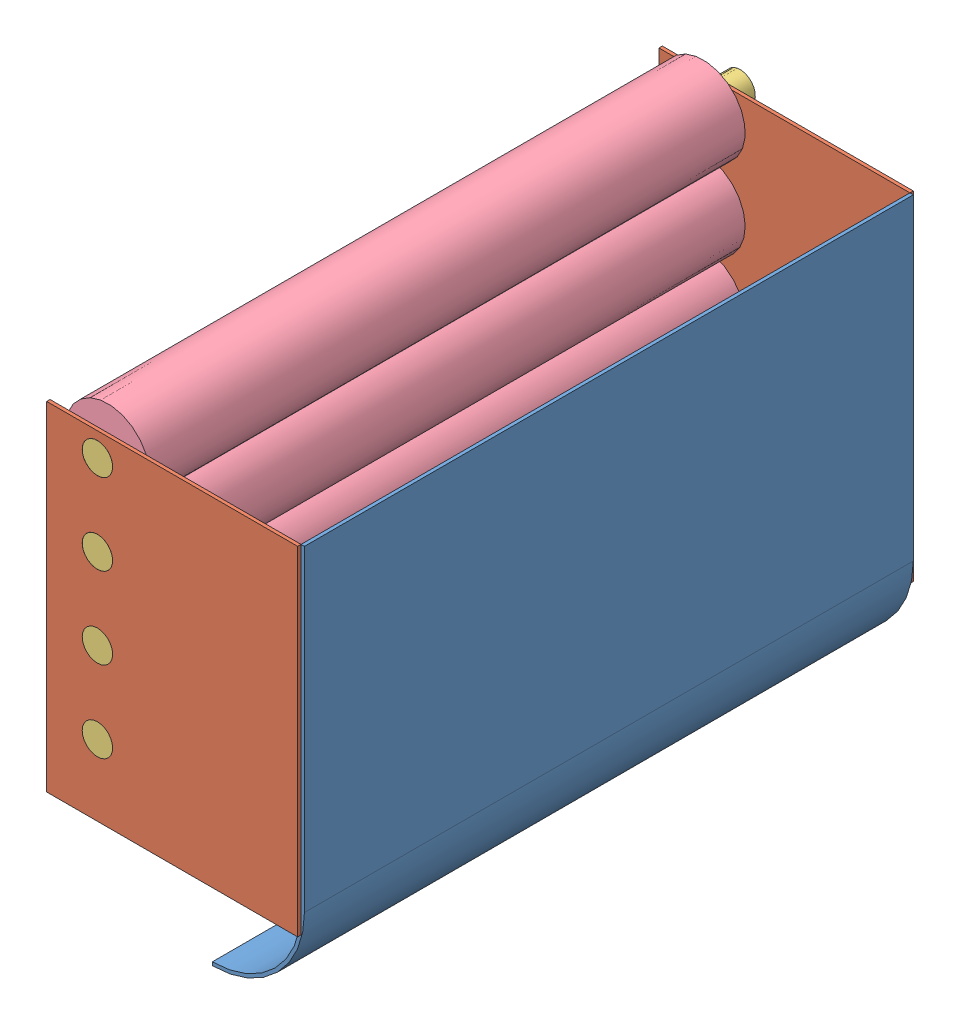
SolidWorks assembly bubbler, configuration Default. Lengths in mm.
Overall size (197.8 331.55 482.6).
11 component instances, 4 part files, 19 mates.
Components (placement in the parent):
- lift-1: lift [Default] at (342.8112 310.4383 211.2872) size (69.22 307.34 457.2)
- plate-1: plate [Default] at (344.2082 421.5633 208.7472) size (188.47 254 2.54)
- plate-2: plate [Default] at (344.2082 421.5633 668.4872) size (188.47 254 2.54)
- axel-1: axel [Default] at (259.1182 530.7833 188.4272) x (0.417742 -0.908566 0) z (0 0 1) size (22.86 22.86 482.6)
- roller-1: roller [Default] at (259.1182 530.7833 216.3672) x (-0.410534 0.911846 0) z (0 0 1) size (63.5 63.5 447.04)
- roller-2: roller [Default] at (259.1182 347.9033 216.3672) x (0.425663 0.904882 0) z (0 0 1) size (63.5 63.5 447.04)
- roller-3: roller [Default] at (259.1182 408.8633 216.3672) x (0.960453 -0.278441 0) z (0 0 1) size (63.5 63.5 447.04)
- roller-4: roller [Default] at (259.1182 469.8233 216.3672) x (0.696531 0.717526 0) z (0 0 1) size (63.5 63.5 447.04)
- axel-2: axel [Default] at (259.1182 408.8633 188.4272) size (22.86 22.86 482.6)
- axel-3: axel [Default] at (259.1182 469.8233 188.4272) x (-0.987013 0.160641 0) z (0 0 1) size (22.86 22.86 482.6)
- axel-4: axel [Default] at (259.1182 347.9033 188.4272) size (22.86 22.86 482.6)
Mates (geometry in assembly coordinates):
- Coincident4: coincident aligned: line of lift-1 through (409.4862 548.5633 668.4872) axis (1 0 0); line of plate-2 through (221.0182 548.5633 668.4872) axis (1 0 0)
- Coincident9: coincident aligned: plane of lift-1 through (409.4862 548.5633 668.4872) normal (0 1 0); plane of plate-2 through (221.0182 548.5633 671.0272) normal (0 1 0)
- Coincident10: coincident aligned: circle of plate-2; circle of axel-1
- Concentric1: concentric anti-aligned: cylinder of axel-1 through (259.1182 530.7833 671.0272) axis (0 0 -1) radius 11.43; cylinder of roller-1 through (259.1182 530.7833 216.3672) axis (0 0 1) radius 11.43
- Coincident12: coincident aligned: circle of plate-2; circle of axel-3
- Coincident14: coincident aligned: circle of plate-2; circle of axel-2
- Coincident16: coincident aligned: circle of plate-2; circle of axel-4
- Coincident17: coincident anti-aligned: circle of roller-4; cylinder of axel-3 through (259.1182 469.8233 671.0272) axis (0 0 -1) radius 11.43
- Concentric2: concentric anti-aligned: cylinder of roller-3 through (259.1182 408.8633 216.3672) axis (0 0 1) radius 11.43; cylinder of axel-2 through (259.1182 408.8633 671.0272) axis (0 0 -1) radius 11.43
- Coincident19: coincident anti-aligned: line of lift-1 through (409.4862 310.4383 668.4872) axis (0 1 0); line of plate-2 through (409.4862 548.5633 668.4872) axis (0 -1 0)
- Coincident20: coincident anti-aligned: line of lift-1 through (409.4862 310.4383 211.2872) axis (0 1 0); line of plate-1 through (409.4862 548.5633 211.2872) axis (0 -1 0)
- Concentric3: concentric anti-aligned: cylinder of roller-2 through (259.1182 347.9033 216.3672) axis (0 0 1) radius 11.43; cylinder of axel-4 through (259.1182 347.9033 671.0272) axis (0 0 -1) radius 11.43
- Parallel5: parallel aligned: plane of lift-1 through (342.8112 310.4383 211.2872) normal (0 0 -1); plane of plate-2 through (344.2082 421.5633 668.4872) normal (0 0 -1)
- Parallel6: parallel aligned: plane of plate-1 through (344.2082 421.5633 211.2872) normal (0 0 1); plane of plate-2 through (344.2082 421.5633 671.0272) normal (0 0 1)
- Coincident23: coincident aligned: plane of lift-1 through (409.4862 548.5633 668.4872) normal (0 1 0); plane of plate-1 through (221.0182 548.5633 211.2872) normal (0 1 0)
- Width1: width aligned: plane of roller-1 through (259.1182 530.7833 216.3672) normal (0 0 -1); plane of roller-1 through (259.1182 530.7833 663.4072) normal (0 0 1); plane of plate-2 through (344.2082 421.5633 668.4872) normal (0 0 -1); plane of plate-1 through (344.2082 421.5633 211.2872) normal (0 0 1)
- Width2: width aligned: plane of roller-4 through (259.1182 469.8233 663.4072) normal (0 0 1); plane of roller-4 through (259.1182 469.8233 216.3672) normal (0 0 -1); plane of plate-1 through (344.2082 421.5633 211.2872) normal (0 0 1); plane of plate-2 through (344.2082 421.5633 668.4872) normal (0 0 -1)
- Width3: width anti-aligned: plane of roller-3 through (259.1182 408.8633 216.3672) normal (0 0 -1); plane of roller-3 through (259.1182 408.8633 663.4072) normal (0 0 1); plane of plate-1 through (344.2082 421.5633 211.2872) normal (0 0 1); plane of plate-2 through (344.2082 421.5633 668.4872) normal (0 0 -1)
- Width4: width anti-aligned: plane of roller-2 through (259.1182 347.9033 216.3672) normal (0 0 -1); plane of roller-2 through (259.1182 347.9033 663.4072) normal (0 0 1); plane of plate-1 through (344.2082 421.5633 211.2872) normal (0 0 1); plane of plate-2 through (344.2082 421.5633 668.4872) normal (0 0 -1)
